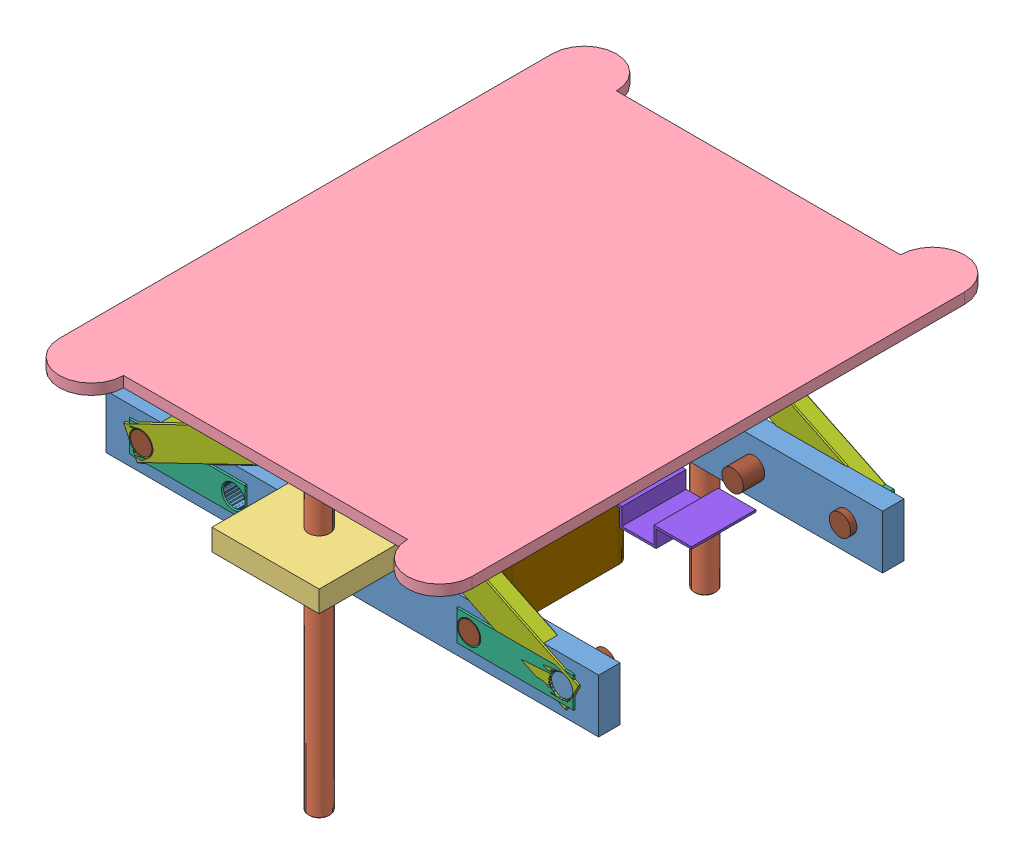
SolidWorks assembly Assem2, configuration Default. Lengths in mm.
Overall size (460 310 520).
31 component instances, 11 part files, 56 mates.
Components (placement in the parent):
- Holding Plate 460 x 50 x 20mm-1: Holding Plate 460 x 50 x 20mm [Default] at (183.5735 194.4044 367.8399) size (460 50 20)
- Holding Plate 460 x 50 x 20mm-2: Holding Plate 460 x 50 x 20mm [Default] at (183.5735 194.4044 102.8399) size (460 50 20)
- Guide Pin 20 x 300mm-1: Guide Pin 20 x 300mm [Default] at (183.5735 10.8248 418.7165) x (-0.502452 0 -0.864605) z (0.864605 0 -0.502452) size (20 300 20)
- Holding Plate for guide Pin-1: Holding Plate for guide Pin [Default] at (183.5735 219.4044 238.7165) x (-1 0 0) z (0 0 -1) size (100 20 460)
- Plate #1-1: Plate #1 [Default] at (183.5735 310.8248 238.7165) size (385 75 520)
- Spring 20 x 25 x 3mm-1: Spring 20 x 25 x 3mm [Default] at (255.6877 280.8248 313.7165) x (1 0 -0.000229) z (0.000229 0 1) size (21 26.99 22.08)
- Toggle 110 x 30 x 15mm-1: Toggle 110 x 30 x 15mm [Default] at (336.5735 194.3597 88.593) x (-0.001041 -0.999999 0) z (0 0 1) size (30 110 15)
- Toggle 200 x 30 x 15mm-1: Toggle 200 x 30 x 15mm [Default] at (300.3235 232.5699 373.8399) x (0.434715 0.900568 0) z (0 0 1) size (30 200 15)
- U Shape Plate-1: U Shape Plate [Default] at (75.9307 245.3182 268.7165) size (395 17.96 60)
- Guide Pin 20 x 300mm-2: Guide Pin 20 x 300mm [Default] at (183.5735 10.8248 58.7165) x (0.467283 0 0.884108) z (-0.884108 0 0.467283) size (20 300 20)
- Toggle 200 x 30 x 15mm-2: Toggle 200 x 30 x 15mm [Default] at (66.8235 232.5699 373.8399) x (0.434715 -0.900568 0) z (0 0 1) size (30 200 15)
- Toggle 200 x 30 x 15mm-3: Toggle 200 x 30 x 15mm [Default] at (300.3235 232.5699 88.593) x (0.434715 0.900568 0) z (0 0 1) size (30 200 15)
- Toggle 200 x 30 x 15mm-4: Toggle 200 x 30 x 15mm [Default] at (66.8235 232.5699 88.593) x (0.434715 -0.900568 0) z (0 0 1) size (30 200 15)
- Toggle 110 x 30 x 15mm-2: Toggle 110 x 30 x 15mm [Default] at (30.5735 194.3597 88.593) x (-0.001041 0.999999 0) z (0 0 1) size (30 110 15)
- Toggle 110 x 30 x 15mm-3: Toggle 110 x 30 x 15mm [Default] at (336.5735 194.3597 373.8399) x (-0.001041 -0.999999 0) z (0 0 1) size (30 110 15)
- Toggle 110 x 30 x 15mm-4: Toggle 110 x 30 x 15mm [Default] at (30.5735 194.3597 373.8399) x (-0.001041 0.999999 0) z (0 0 1) size (30 110 15)
- Air Cylynder Body 50 x 50-1: Air Cylynder Body 50 x 50 [Default] at (183.5735 119.4044 238.7165) size (100 100 120)
- Shaft 25mm-1: Shaft 25mm [Default] at (183.5735 130.3182 238.7165) x (0 0 1) z (-1 0 0) size (86 117 86)
- Spring 20 x 25 x 3mm-2: Spring 20 x 25 x 3mm [Default] at (110.295 280.8248 238.7165) x (1 0 -0.000229) z (0.000229 0 1) size (21 26.99 22.08)
- Spring 20 x 25 x 3mm-3: Spring 20 x 25 x 3mm [Default] at (255.6877 280.8248 163.7165) x (1 0 -0.000229) z (0.000229 0 1) size (21 26.99 22.08)
- Spring 20 x 25 x 3mm-4: Spring 20 x 25 x 3mm [Default] at (255.6877 280.8248 238.7165) x (1 0 -0.000229) z (0.000229 0 1) size (21 26.99 22.08)
- Spring 20 x 25 x 3mm-5: Spring 20 x 25 x 3mm [Default] at (110.295 280.8248 163.7165) x (1 0 -0.000229) z (0.000229 0 1) size (21 26.99 22.08)
- Spring 20 x 25 x 3mm-6: Spring 20 x 25 x 3mm [Default] at (110.295 280.8248 313.7165) x (1 0 -0.000229) z (0.000229 0 1) size (21 26.99 22.08)
- Pin 20 x 40 mm-1: Pin 20 x 40 mm [Default] at (379.5735 194.3149 88.593) x (0.931974 -0.362526 0) z (-0.362526 -0.931974 0) size (20 40 20)
- Pin 20 x 40 mm-2: Pin 20 x 40 mm [Default] at (379.5735 194.3149 347.8399) x (-0.74599 -0.665958 0) z (-0.665958 0.74599 0) size (20 40 20)
- Pin 20 x 40 mm-3: Pin 20 x 40 mm [Default] at (-12.4264 194.3149 62.593) x (0.964998 -0.262255 0) z (-0.262255 -0.964998 0) size (20 40 20)
- Pin 20 x 40 mm-4: Pin 20 x 40 mm [Default] at (-12.4264 194.3149 348.8399) x (0.931974 -0.362526 0) z (-0.362526 -0.931974 0) size (20 40 20)
- Pin 20 x 40 mm-5: Pin 20 x 40 mm [Default] at (293.5735 194.4044 102.8399) x (0.931586 -0.36352 0) z (-0.36352 -0.931586 0) size (20 40 20)
- Pin 20 x 40 mm-6: Pin 20 x 40 mm [Default] at (73.5735 194.4044 327.8399) x (0.931586 -0.36352 0) z (-0.36352 -0.931586 0) size (20 40 20)
- Pin 20 x 40 mm-7: Pin 20 x 40 mm [Default] at (73.586 197.9327 102.8399) x (0.931586 -0.36352 0) z (-0.36352 -0.931586 0) size (20 40 20)
- Pin 20 x 40 mm-8: Pin 20 x 40 mm [Default] at (293.5735 194.4044 348.8399) x (0.931586 -0.36352 0) z (-0.36352 -0.931586 0) size (20 40 20)
Mates (geometry in assembly coordinates):
- Coincident1: coincident: plane of assembly; plane of assembly; plane of Holding Plate 460 x 50 x 20mm-1 through (-46.4265 219.4044 387.8399) normal (0 1 0); plane of Air Cylynder Body 50 x 50-1 through (223.5735 219.4044 288.7165) normal (0 1 0)
- Distance1: distance = 245 mm: plane of assembly; plane of assembly; plane of Holding Plate 460 x 50 x 20mm-2 through (183.5735 194.4044 122.8399) normal (0 0 1); plane of Holding Plate 460 x 50 x 20mm-1 through (183.5735 194.4044 367.8399) normal (0 0 -1)
- Coincident3: coincident: plane of assembly; plane of assembly; plane of Holding Plate 460 x 50 x 20mm-1 through (-46.4265 219.4044 387.8399) normal (0 1 0); plane of Holding Plate 460 x 50 x 20mm-2 through (-46.4265 219.4044 122.8399) normal (0 1 0)
- Coincident4: coincident: plane of assembly; plane of assembly; plane of Holding Plate 460 x 50 x 20mm-1 through (-46.4265 219.4044 387.8399) normal (-1 0 0); plane of Holding Plate 460 x 50 x 20mm-2 through (-46.4265 219.4044 122.8399) normal (-1 0 0)
- Coincident8: coincident: circle of assembly; circle of assembly; circle of Holding Plate for guide Pin-1; circle of Air Cylynder Body 50 x 50-1
- Distance4: distance = 180 mm: plane of assembly; plane of assembly; plane of Air Cylynder Body 50 x 50-1 through (233.5735 219.4044 188.7165) normal (1 0 0); plane of Holding Plate 460 x 50 x 20mm-1 through (413.5735 219.4044 387.8399) normal (1 0 0)
- Parallel1: parallel: plane of assembly; plane of assembly; plane of Holding Plate 460 x 50 x 20mm-1 through (413.5735 219.4044 387.8399) normal (1 0 0); plane of Holding Plate for guide Pin-1 through (233.5735 239.4044 468.7165) normal (1 0 0)
- Coincident12: coincident: circle of assembly; circle of assembly; circle of Plate #1-1; circle of Spring 20 x 25 x 3mm-1
- Coincident13: coincident: circle of assembly; circle of assembly; circle of Plate #1-1; circle of Spring 20 x 25 x 3mm-4
- Coincident14: coincident: circle of assembly; circle of assembly; circle of Plate #1-1; circle of Spring 20 x 25 x 3mm-3
- Coincident15: coincident: circle of assembly; circle of assembly; circle of Plate #1-1; circle of Spring 20 x 25 x 3mm-6
- Coincident16: coincident: circle of assembly; circle of assembly; circle of Plate #1-1; circle of Spring 20 x 25 x 3mm-2
- Coincident17: coincident: circle of assembly; circle of assembly; circle of Plate #1-1; circle of Spring 20 x 25 x 3mm-5
- Concentric2: concentric: circle of assembly; circle of assembly; circle of Plate #1-1; circle of Toggle 200 x 30 x 15mm-1
- Coincident18: coincident: plane of assembly; plane of assembly; plane of Plate #1-1 through (221.0735 270.8248 388.8399) normal (0 0 1); plane of Toggle 200 x 30 x 15mm-1 through (300.3235 232.5699 388.8399) normal (0 0 1)
- Concentric3: concentric: circle of assembly; circle of assembly; circle of Plate #1-1; circle of Toggle 200 x 30 x 15mm-2
- Coincident19: coincident: plane of assembly; plane of assembly; plane of Plate #1-1 through (146.0735 270.8248 388.8399) normal (0 0 1); plane of Toggle 200 x 30 x 15mm-2 through (66.8235 232.5699 388.8399) normal (0 0 1)
- Concentric4: concentric: circle of assembly; circle of assembly; circle of Plate #1-1; circle of Toggle 200 x 30 x 15mm-4
- Coincident20: coincident: plane of assembly; plane of assembly; plane of Plate #1-1 through (146.0735 270.8248 88.593) normal (0 0 -1); plane of Toggle 200 x 30 x 15mm-4 through (66.8235 232.5699 88.593) normal (0 0 -1)
- Concentric5: concentric: circle of assembly; circle of assembly; circle of Plate #1-1; circle of Toggle 200 x 30 x 15mm-3
- Coincident21: coincident: plane of assembly; plane of assembly; plane of Plate #1-1 through (221.0735 270.8248 88.593) normal (0 0 -1); plane of Toggle 200 x 30 x 15mm-3 through (300.3235 232.5699 88.593) normal (0 0 -1)
- Coincident23: coincident: plane of assembly; plane of assembly; plane of Toggle 200 x 30 x 15mm-2 through (66.8235 232.5699 388.8399) normal (0 0 1); plane of Toggle 110 x 30 x 15mm-4 through (30.5735 194.3597 388.8399) normal (0 0 1)
- Concentric6: concentric: circle of assembly; circle of assembly; circle of Toggle 200 x 30 x 15mm-2; circle of Toggle 110 x 30 x 15mm-4
- Coincident24: coincident: plane of assembly; plane of assembly; plane of Toggle 200 x 30 x 15mm-1 through (300.3235 232.5699 388.8399) normal (0 0 1); plane of Toggle 110 x 30 x 15mm-3 through (336.5735 194.3597 388.8399) normal (0 0 1)
- Concentric7: concentric: circle of assembly; circle of assembly; circle of Toggle 200 x 30 x 15mm-1; circle of Toggle 110 x 30 x 15mm-3
- Coincident25: coincident: plane of assembly; plane of assembly; plane of Toggle 110 x 30 x 15mm-1 through (336.5735 194.3597 103.593) normal (0 0 1); plane of Toggle 200 x 30 x 15mm-3 through (300.3235 232.5699 103.593) normal (0 0 1)
- Concentric8: concentric: circle of assembly; circle of assembly; circle of Toggle 110 x 30 x 15mm-1; circle of Toggle 200 x 30 x 15mm-3
- Coincident26: coincident: plane of assembly; plane of assembly; plane of Toggle 200 x 30 x 15mm-4 through (66.8235 232.5699 103.593) normal (0 0 1); plane of Toggle 110 x 30 x 15mm-2 through (30.5735 194.3597 103.593) normal (0 0 1)
- Coincident27: coincident: circle of assembly; circle of assembly; circle of Toggle 200 x 30 x 15mm-4; circle of Toggle 110 x 30 x 15mm-2
- Concentric9: concentric: circle of assembly; circle of assembly; circle of Toggle 110 x 30 x 15mm-4; circle of Pin 20 x 40 mm-4
- Coincident28: coincident: plane of assembly; plane of assembly; plane of Toggle 110 x 30 x 15mm-4 through (30.5735 194.3597 388.8399) normal (0 0 1); plane of Pin 20 x 40 mm-4 through (-12.4264 194.3149 388.8399) normal (0 0 1)
- Coincident29: coincident: circle of assembly; circle of assembly; circle of Toggle 200 x 30 x 15mm-4; circle of Pin 20 x 40 mm-3
- Coincident32: coincident: circle of assembly; circle of assembly; circle of Toggle 110 x 30 x 15mm-3; circle of Pin 20 x 40 mm-2
- Concentric10: concentric: circle of assembly; circle of assembly; circle of Toggle 200 x 30 x 15mm-3; circle of Pin 20 x 40 mm-1
- Coincident33: coincident: cylinder of assembly; circle of assembly; cylinder of Holding Plate 460 x 50 x 20mm-1 through (293.5735 194.4044 387.8399) axis (0 0 -1) radius 10; circle of Pin 20 x 40 mm-8
- Coincident34: coincident: circle of assembly; circle of assembly; circle of Holding Plate 460 x 50 x 20mm-1; circle of Toggle 110 x 30 x 15mm-3
- Coincident35: coincident: plane of assembly; plane of assembly; plane of Toggle 110 x 30 x 15mm-3 through (336.5735 194.3597 388.8399) normal (0 0 1); plane of Pin 20 x 40 mm-8 through (293.5735 194.4044 388.8399) normal (0 0 1)
- Concentric11: concentric: circle of assembly; circle of assembly; circle of Holding Plate 460 x 50 x 20mm-1; circle of Toggle 110 x 30 x 15mm-4
- Coincident36: coincident: circle of assembly; circle of assembly; circle of Holding Plate 460 x 50 x 20mm-1; circle of Pin 20 x 40 mm-6
- Concentric12: concentric: circle of assembly; circle of assembly; circle of Holding Plate 460 x 50 x 20mm-2; circle of Toggle 110 x 30 x 15mm-2
- Coincident43: coincident: circle of assembly; plane of assembly; circle of Holding Plate 460 x 50 x 20mm-2; plane of Pin 20 x 40 mm-7 through (73.586 197.9327 102.8399) normal (0 0 -1)
- Coincident44: coincident: circle of assembly; circle of assembly; circle of Holding Plate 460 x 50 x 20mm-2; circle of Pin 20 x 40 mm-5
- Concentric13: concentric: circle of assembly; circle of assembly; circle of Toggle 110 x 30 x 15mm-1; circle of Pin 20 x 40 mm-5
- Coincident45: coincident: plane of assembly; circle of assembly; plane of Toggle 110 x 30 x 15mm-1 through (336.5735 194.3597 88.593) normal (0 0 -1); circle of Pin 20 x 40 mm-1
- Concentric14: concentric: circle of assembly; circle of assembly; circle of Holding Plate for guide Pin-1; circle of Plate #1-1
- Concentric15: concentric: circle of assembly; circle of assembly; circle of Holding Plate for guide Pin-1; circle of U Shape Plate-1
- Coincident55: coincident: plane of Holding Plate for guide Pin-1 through (183.5735 239.4044 238.7165) normal (0 1 0); plane of ? through (314.0735 239.4044 208.7165) normal (0 -1 0)
- Concentric16: concentric: circle of assembly; circle of assembly; circle of Holding Plate for guide Pin-1; circle of Guide Pin 20 x 300mm-2
- Coincident57: coincident: plane of assembly; plane of assembly; plane of Plate #1-1 through (346.0735 310.8248 468.7165) normal (0 -1 0); plane of Guide Pin 20 x 300mm-2 through (183.5735 310.8248 58.7165) normal (0 1 0)
- Concentric17: concentric: circle of assembly; circle of assembly; circle of Guide Pin 20 x 300mm-1; circle of Holding Plate for guide Pin-1
- Coincident58: coincident: plane of assembly; plane of assembly; plane of Guide Pin 20 x 300mm-1 through (183.5735 310.8248 418.7165) normal (0 1 0); plane of Plate #1-1 through (346.0735 310.8248 468.7165) normal (0 -1 0)
- Concentric18: concentric: circle of assembly; circle of assembly; circle of Holding Plate for guide Pin-1; circle of Shaft 25mm-1
- Parallel10: parallel: line of assembly; line of assembly; line of Air Cylynder Body 50 x 50-1 through (233.5735 119.4044 288.7165) axis (0 0 -1); line of Shaft 25mm-1 through (226.5735 130.3182 281.7165) axis (0 0 -1)
- LimitDistance2: limit distance = 10.9138 mm: plane of assembly; line of assembly; plane of Shaft 25mm-1 through (183.5735 130.3182 238.7165) normal (0 -1 0); line of Air Cylynder Body 50 x 50-1 through (231.5735 119.4044 190.7165) axis (0 0 1)
- Coincident67: coincident: circle of assembly; circle of assembly; circle of U Shape Plate-1; circle of Shaft 25mm-1
- Parallel12: parallel: line of assembly; line of assembly; line of Holding Plate 460 x 50 x 20mm-2 through (413.5735 219.4044 102.8399) axis (-1 0 0); line of U Shape Plate-1 through (316.0735 247.3182 208.7165) axis (-1 0 0)
